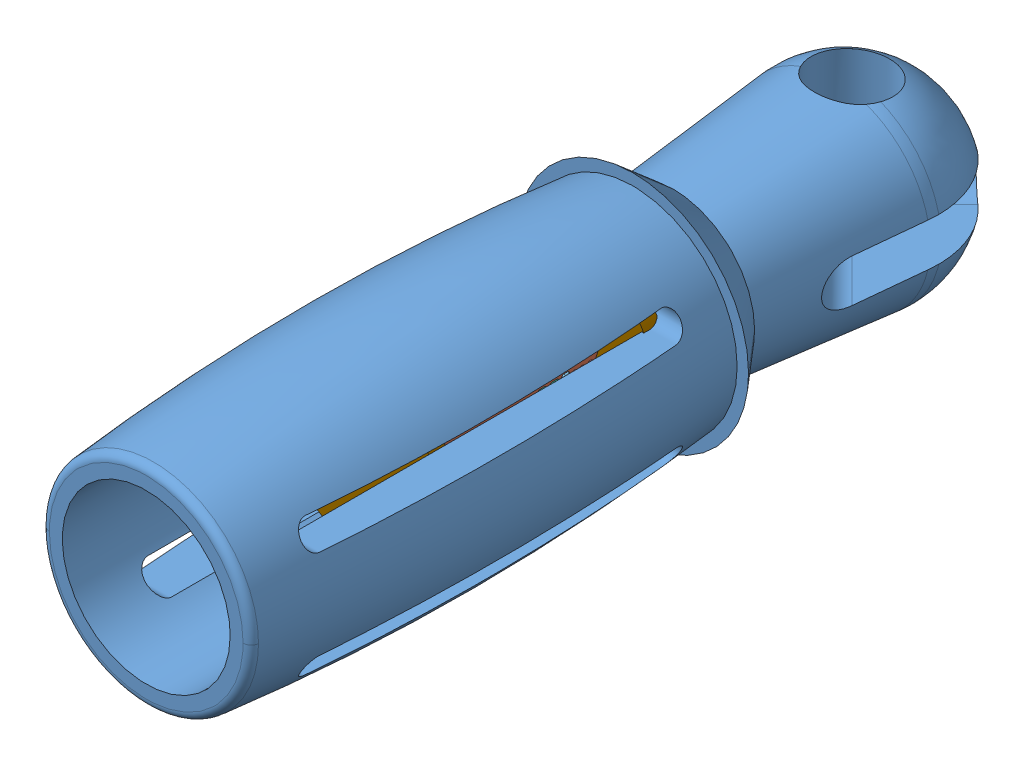
SolidWorks assembly Connector, configuration Default. Lengths in mm.
Overall size (31.63 31.63 98).
26 component instances, 10 part files, 5 mates.
Components (placement in the parent):
- airXBallJoint-1: airXBallJoint [Default] at (-10.3592 134.4578 135.9866) size (31.63 31.63 98)
- MPU 6050 IMU.STEP-1: MPU 6050 IMU.STEP [Default] at (-3.153 80.5692 102.6428) x (0.006639 0.032964 -0.999434) z (-0.325644 -0.944905 -0.033329) size (21.11 2.74 15.75)
  - Base.STEP-1: Base.STEP [Default] at (7.2489 10.9584 16.5726) size (21.11 1.14 15.75)
  - pin header.STEP-1: pin header.STEP [Default] at (16.0246 10.3869 9.8416) x (-1 0 0) z (0 0 1) size (2.54 11.18 2.54) (hidden)
  - pin header.STEP-2: pin header.STEP [Default] at (13.4846 10.3869 9.8416) x (-1 0 0) z (0 0 1) size (2.54 11.18 2.54) (hidden)
  - pin header.STEP-3: pin header.STEP [Default] at (10.9446 10.3869 9.8416) x (-1 0 0) z (0 0 1) size (2.54 11.18 2.54) (hidden)
  - pin header.STEP-4: pin header.STEP [Default] at (8.4046 10.3869 9.8416) x (-1 0 0) z (0 0 1) size (2.54 11.18 2.54) (hidden)
  - pin header.STEP-5: pin header.STEP [Default] at (5.8646 10.3869 9.8416) x (-1 0 0) z (0 0 1) size (2.54 11.18 2.54) (hidden)
  - pin header.STEP-6: pin header.STEP [Default] at (3.3246 10.3869 9.8416) x (-1 0 0) z (0 0 1) size (2.54 11.18 2.54) (hidden)
  - pin header.STEP-7: pin header.STEP [Default] at (0.7846 10.3869 9.8416) x (-1 0 0) z (0 0 1) size (2.54 11.18 2.54) (hidden)
  - pin header.STEP-8: pin header.STEP [Default] at (-1.7554 10.3869 9.8416) x (-1 0 0) z (0 0 1) size (2.54 11.18 2.54) (hidden)
  - sensor chip.STEP-1: sensor chip.STEP [Default] at (7.2489 11.5499 17.4466) size (5.4 0.9 5.4)
  - S2NH chip.STEP-1: S2NH chip.STEP [Default] at (16.1026 12.3799 16.5726) size (3 1.35 3.65)
  - Resistor small.STEP-1: Resistor small.STEP [Default] at (16.1026 11.5314 19.3726) size (2.75 0.94 0.95)
  - Resistor small.STEP-2: Resistor small.STEP [Default] at (13.9776 11.5314 15.6976) x (0 0 -1) z (1 0 0) size (2.75 0.94 0.95)
  - Resistor small black.STEP-1: Resistor small black.STEP [Default] at (12.6276 11.5299 15.6976) x (0 0 1) z (-1 0 0) size (2.45 0.54 0.95)
  - Resistor small black.STEP-2: Resistor small black.STEP [Default] at (11.1276 11.5299 15.6976) x (0 0 1) z (-1 0 0) size (2.45 0.54 0.95)
  - Resistor small.STEP-3: Resistor small.STEP [Default] at (12.6276 11.5314 19.3216) x (0 0 -1) z (1 0 0) size (2.75 0.94 0.95)
  - Resistor small.STEP-4: Resistor small.STEP [Default] at (11.1276 11.5314 19.3216) x (0 0 -1) z (1 0 0) size (2.75 0.94 0.95)
  - Resistor small.STEP-5: Resistor small.STEP [Default] at (3.3702 11.5314 19.3216) x (0 0 -1) z (1 0 0) size (2.75 0.94 0.95)
  - Resistor small black.STEP-3: Resistor small black.STEP [Default] at (1.8702 11.5299 15.6968) x (0 0 -1) z (1 0 0) size (2.45 0.54 0.95)
  - Resistor small.STEP-6: Resistor small.STEP [Default] at (3.3702 11.5314 15.6976) x (0 0 1) z (-1 0 0) size (2.75 0.94 0.95)
  - Small LED.STEP-1: Small LED.STEP [Default] at (0.3652 11.5299 15.6976) size (0.85 0.84 1.9)
  - Resistor small black.STEP-4: Resistor small black.STEP [Default] at (1.8702 11.5299 19.3216) x (0 0 1) z (-1 0 0) size (2.45 0.54 0.95)
  - Resistor black.STEP-1: Resistor black.STEP [Default] at (7.2489 12.3799 21.6466) size (4.2 1.6 1.6)
- circle gyro bracket-1: circle gyro bracket [Default] at (4.6463 71.5767 83.7674) x (-0.006639 -0.032964 0.999434) z (-0.945469 0.325681 0.004461) size (28 20 20)
Mates (geometry in assembly coordinates):
- Parallel1: parallel anti-aligned: plane of MPU 6050 IMU.STEP-1/Base.STEP-1 through (-0.2347 53.6054 105.0795) normal (-0.006639 -0.032964 0.999434); plane of circle gyro bracket-1 through (-0.8076 63.0956 107.4651) normal (0.006639 0.032964 -0.999434)
- Parallel3: parallel aligned: plane of MPU 6050 IMU.STEP-1/Base.STEP-1 through (4.8935 68.4858 105.6043) normal (0.325644 0.944905 0.033329); plane of circle gyro bracket-1 through (-0.0811 73.2051 83.7897) normal (0.325644 0.944905 0.033329)
- Parallel4: parallel aligned: plane of MPU 6050 IMU.STEP-1/Base.STEP-1 through (-0.2347 53.6054 105.0795) normal (-0.325644 -0.944905 -0.033329); plane of circle gyro bracket-1 through (-5.9427 56.1968 83.1898) normal (-0.325644 -0.944905 -0.033329)
- Coincident13: coincident: line of MPU 6050 IMU.STEP-1/Base.STEP-1 through (-1.1753 54.6735 83.9891) axis (0.325644 0.944905 0.033329); plane of circle gyro bracket-1 through (4.6463 71.5767 83.7674) normal (0.945469 -0.325681 -0.004461)
- Concentric5: concentric anti-aligned: circle of MPU 6050 IMU.STEP-1/Base.STEP-1; circle of circle gyro bracket-1
